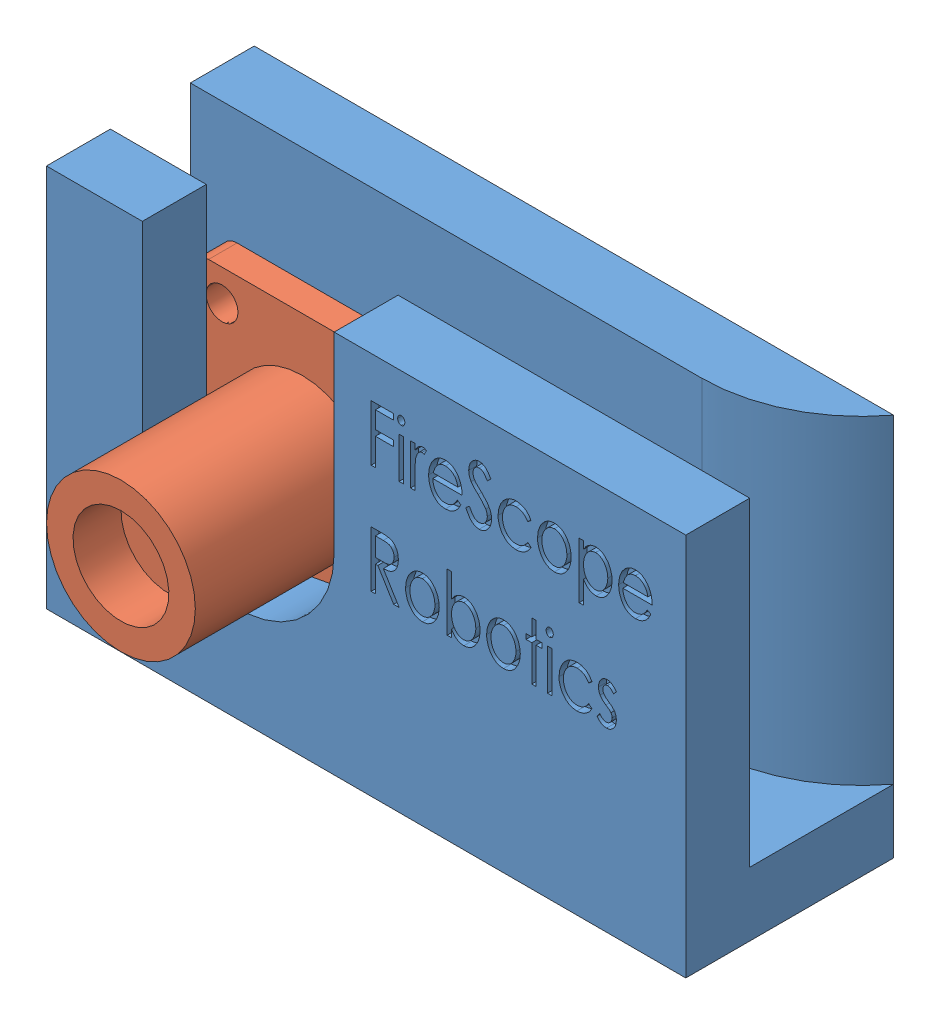
SolidWorks assembly IR_cam_and_holder, configuration Default. Lengths in mm.
Overall size (40 24 20.34).
2 component instances, 2 part files, 3 mates.
Components (placement in the parent):
- IR_camera-1: IR_camera [Default] at (1.8144 19.4517 51.7822) size (40 24 13)
- MLX90640-1: MLX90640 [Default] at (21.0994 31.4517 46.0022) x (0 1 0) z (0 0 1) size (16.02 28.28 13.12)
Mates (geometry in assembly coordinates):
- Concentric1: concentric anti-aligned: cylinder of IR_camera-1 through (13.8144 31.4517 47.7822) axis (0 0 1) radius 6; cylinder of MLX90640-1 through (13.8144 31.4517 59.1222) axis (0 0 -1) radius 4.655
- Parallel1: parallel anti-aligned: plane of IR_camera-1 through (41.8144 23.4517 47.7822) normal (0 1 0); plane of MLX90640-1 through (35.2394 23.4417 47.7822) normal (0 -1 0)
- Coincident2: coincident anti-aligned: plane of IR_camera-1 through (41.8144 43.4517 47.7822) normal (0 0 -1); plane of MLX90640-1 through (7.9594 38.4617 47.7822) normal (0 0 1)
